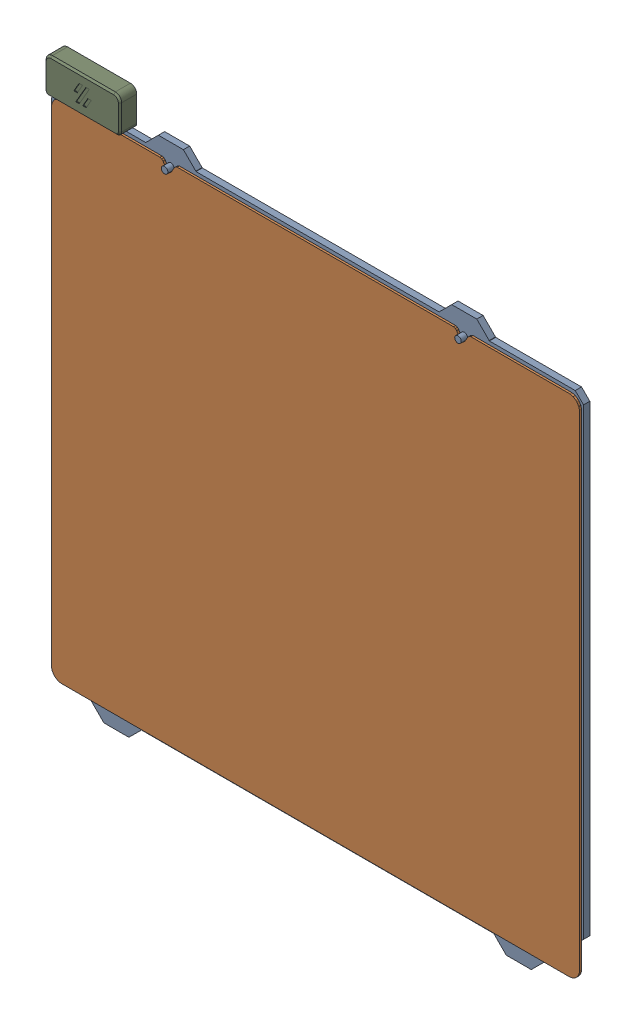
SolidWorks assembly Prusa MK3_Bed_assembly v2, configuration Default. Lengths in mm.
Overall size (253.8 266.5 15.8).
21 component instances, 13 part files, 0 mates.
Components (placement in the parent):
- MK52_Bed001-1: MK52_Bed001 [Default] at (53 -177.7907 -175.175) x (1 0 0) z (0 -1 0) size (253.8 6 264.25)
- flex-sheet001-1: flex-sheet001 [Default] at (53.8544 -185.6984 -172.175) x (1 0 0) z (0 -1 0) size (252 1 241)
- 6x6x3t_spacer_010-1: 6x6x3t_spacer_010 [Default] at (70 42.2507 -175.175) x (1 0 0) z (0 1 0) size (6 6 6)
- 6x6x3t_spacer_017-1: 6x6x3t_spacer_017 [Default] at (180 -167.7493 -175.175) x (1 0 0) z (0 1 0) size (6 6 6)
- 6x6x3t_spacer_014-1: 6x6x3t_spacer_014 [Default] at (70 -62.7493 -175.175) x (1 0 0) z (0 1 0) size (6 6 6)
- 6x6x3t_spacer_013-1: 6x6x3t_spacer_013 [Default] at (180 -62.7493 -175.175) x (1 0 0) z (0 1 0) size (6 6 6)
- 6x6x3t_spacer_012-1: 6x6x3t_spacer_012 [Default] at (285 -62.7493 -175.175) x (1 0 0) z (0 1 0) size (6 6 6)
- 6x6x3t_spacer_016-1: 6x6x3t_spacer_016 [Default] at (285 -167.7493 -175.175) x (1 0 0) z (0 1 0) size (6 6 6)
- 6x6x3t_spacer_018-1: 6x6x3t_spacer_018 [Default] at (70 -167.7493 -175.175) x (1 0 0) z (0 1 0) size (6 6 6)
- 6x6x3t_spacer_011-1: 6x6x3t_spacer_011 [Default] at (180 42.2507 -175.175) x (1 0 0) z (0 1 0) size (6 6 6)
- 6x6x3t_spacer_015-1: 6x6x3t_spacer_015 [Default] at (285 42.2507 -175.175) x (1 0 0) z (0 1 0) size (6 6 6)
- M3x12 FHCS-1: M3x12 FHCS [Default] at (70 -167.7493 -172.175) size (6 6 12.12)
- M3x12 FHCS-2: M3x12 FHCS [Default] at (285 -62.7493 -172.175) size (6 6 12.12)
- M3x12 FHCS-3: M3x12 FHCS [Default] at (70 42.2507 -172.175) size (6 6 12.12)
- M3x12 FHCS-4: M3x12 FHCS [Default] at (180 -167.7493 -172.175) size (6 6 12.12)
- M3x12 FHCS-5: M3x12 FHCS [Default] at (285 42.2507 -172.175) size (6 6 12.12)
- M3x12 FHCS-6: M3x12 FHCS [Default] at (70 -62.7493 -172.175) size (6 6 12.12)
- M3x12 FHCS-7: M3x12 FHCS [Default] at (180 -62.7493 -172.175) size (6 6 12.12)
- M3x12 FHCS-8: M3x12 FHCS [Default] at (180 42.2507 -172.175) size (6 6 12.12)
- M3x12 FHCS-9: M3x12 FHCS [Default] at (285 -167.7493 -172.175) size (6 6 12.12)
- Heatbed Terminals Cover-1: Heatbed Terminals Cover [Default] at (59.1603 -141.2907 -230.175) x (-1 0 0) z (0 0 -1) size (36 17.1 8)
